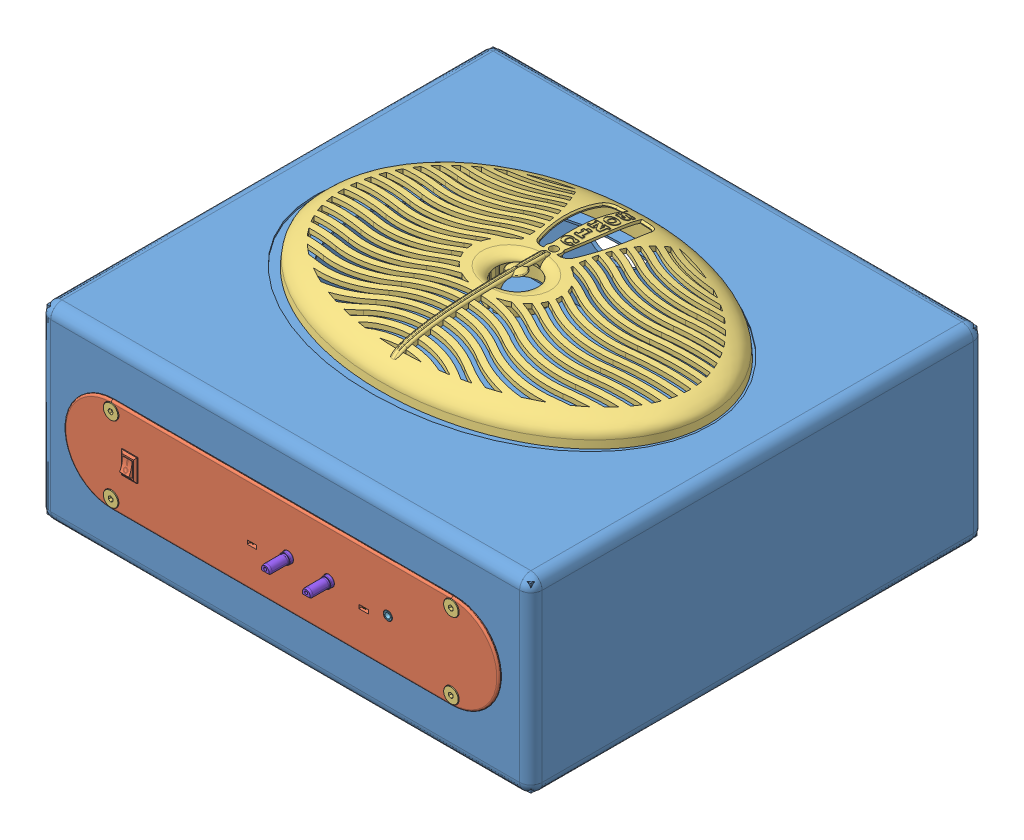
SolidWorks assembly HappyTunesAssembly, configuration Default. Lengths in mm.
Overall size (330.2 155.84 325.49).
147 component instances, 21 part files, 13 mates.
Components (placement in the parent):
- SpeakerBox-1: SpeakerBox [Default] at (77.636 124.7936 266.6745) size (330.2 127 304.8)
- FacePlate-1: FacePlate [Default] at (77.636 188.2936 419.0745) size (292.1 63.5 2.54)
- User Library-6x9 marine speaker-grille-1: User Library-6x9 marine speaker-grille [Default] at (78.9977 250.5236 265.0729) size (279.28 30.11 201.86)
- GateDriver-1: GateDriver [Default] at (239.7422 178.354 452.5745) x (-0.999998 0.002225 0) z (0.002225 0.999998 0) size (183.5 153.69 35.98)
  - GateDriver.step-1: GateDriver.step [Default] at origin size (183.5 153.69 35.98)
    - C_Rect_L7.0mm_W2.5mm_P5.00mm.step-1: C_Rect_L7.0mm_W2.5mm_P5.00mm.step [Default] at (155 -55 1.65) size (7 2.5 11.9)
      - SOLID.step-1: SOLID.step [Default] at origin size (7 2.5 11.9)
    - C_Rect_L7.0mm_W2.5mm_P5.00mm.step-2: C_Rect_L7.0mm_W2.5mm_P5.00mm.step [Default] at (151 -150.5 1.65) size (7 2.5 11.9)
      - SOLID.step-1: SOLID.step [Default] at origin size (7 2.5 11.9)
    - C_Rect_L7.0mm_W2.5mm_P5.00mm.step-3: C_Rect_L7.0mm_W2.5mm_P5.00mm.step [Default] at (164 -55 1.65) size (7 2.5 11.9)
      - SOLID.step-1: SOLID.step [Default] at origin size (7 2.5 11.9)
    - C_Rect_L7.0mm_W2.5mm_P5.00mm.step-4: C_Rect_L7.0mm_W2.5mm_P5.00mm.step [Default] at (139 -150.5 1.65) size (7 2.5 11.9)
      - SOLID.step-1: SOLID.step [Default] at origin size (7 2.5 11.9)
    - C_Rect_L7.0mm_W2.5mm_P5.00mm.step-5: C_Rect_L7.0mm_W2.5mm_P5.00mm.step [Default] at (112 -104.5 1.65) size (7 2.5 11.9)
      - SOLID.step-1: SOLID.step [Default] at origin size (7 2.5 11.9)
    - C_Rect_L7.0mm_W2.5mm_P5.00mm.step-6: C_Rect_L7.0mm_W2.5mm_P5.00mm.step [Default] at (112 -96.5 1.65) size (7 2.5 11.9)
      - SOLID.step-1: SOLID.step [Default] at origin size (7 2.5 11.9)
    - CUI_DEVICES_SJ1-3533NG.step-1: CUI_DEVICES_SJ1-3533NG.step [Default] at (90.5 -30.8 9.15) x (0 1 0) z (0 0 -1) size (18.05 8.2 15.6)
      - SOLID-0.step-1: SOLID-0.step [Default] at origin size (18.05 8.2 15.6)
    - PinHeader_1x06_P2.54mm_Vertical.step-1: PinHeader_1x06_P2.54mm_Vertical.step [Default] at (58.5 -55 1.65) x (-1 0 0) z (0 0 1) size (2.54 15.24 11.54)
      - SOLID-1.step-1: SOLID-1.step [Default] at origin size (2.54 15.24 11.54)
    - R_Axial_DIN0204_L3.6mm_D1.6mm_P7.62mm_Horizontal.step-1: R_Axial_DIN0204_L3.6mm_D1.6mm_P7.62mm_Horizontal.step [Default] at (71 -41.5 1.65) x (-1 0 0) z (0 0 1) size (8.12 1.6 4.72)
      - SOLID-2.step-1: SOLID-2.step [Default] at origin size (8.12 1.6 4.72)
    - R_Axial_DIN0204_L3.6mm_D1.6mm_P7.62mm_Horizontal.step-2: R_Axial_DIN0204_L3.6mm_D1.6mm_P7.62mm_Horizontal.step [Default] at (71 -47 1.65) x (-1 0 0) z (0 0 1) size (8.12 1.6 4.72)
      - SOLID-2.step-1: SOLID-2.step [Default] at origin size (8.12 1.6 4.72)
    - R_Axial_DIN0204_L3.6mm_D1.6mm_P7.62mm_Horizontal.step-3: R_Axial_DIN0204_L3.6mm_D1.6mm_P7.62mm_Horizontal.step [Default] at (82 -47 1.65) x (0 1 0) z (0 0 1) size (8.12 1.6 4.72)
      - SOLID-2.step-1: SOLID-2.step [Default] at origin size (8.12 1.6 4.72)
    - R_Axial_DIN0204_L3.6mm_D1.6mm_P7.62mm_Horizontal.step-4: R_Axial_DIN0204_L3.6mm_D1.6mm_P7.62mm_Horizontal.step [Default] at (97.5 -51 1.65) x (0 1 0) z (0 0 1) size (8.12 1.6 4.72)
      - SOLID-2.step-1: SOLID-2.step [Default] at origin size (8.12 1.6 4.72)
    - R_Axial_DIN0204_L3.6mm_D1.6mm_P7.62mm_Horizontal.step-5: R_Axial_DIN0204_L3.6mm_D1.6mm_P7.62mm_Horizontal.step [Default] at (153.5 -49.5 1.65) size (8.12 1.6 4.72)
      - SOLID-2.step-1: SOLID-2.step [Default] at origin size (8.12 1.6 4.72)
    - R_Axial_DIN0204_L3.6mm_D1.6mm_P7.62mm_Horizontal.step-6: R_Axial_DIN0204_L3.6mm_D1.6mm_P7.62mm_Horizontal.step [Default] at (164 -49.5 1.65) size (8.12 1.6 4.72)
      - SOLID-2.step-1: SOLID-2.step [Default] at origin size (8.12 1.6 4.72)
    - User Library-K091B0Z94 v1.step-1: User Library-K091B0Z94 v1.step [Default] at (157.5 -34 9.65) x (1 0 0) z (0 -1 0) size (9.8 16.06 30.49)
      - COMPOUND.step-1: COMPOUND.step [Default] at origin size (9.8 16.06 30.49)
    - User Library-K091B0Z94 v1.step-2: User Library-K091B0Z94 v1.step [Default] at (130 -34 9.65) x (1 0 0) z (0 -1 0) size (9.8 16.06 30.49)
      - COMPOUND.step-1: COMPOUND.step [Default] at origin size (9.8 16.06 30.49)
    - 3Pins SPDT switch SK-12D07 1P2T.step-1: 3Pins SPDT switch SK-12D07 1P2T.step [Default] at (111.35 -34.7 6.65) x (-1 0 0) z (0 0 1) size (8.6 6.94 7.5)
      - COMPOUND-3.step-1: COMPOUND-3.step [Default] at origin size (8.6 6.94 7.5)
    - SW_CuK_JS202011AQN_DPDT_Angled.step-1: SW_CuK_JS202011AQN_DPDT_Angled.step [Default] at (130.5 -59.5 1.65) x (-1 0 0) z (0 0 1) size (9 5.6 6.5)
      - SOLID-4.step-1: SOLID-4.step [Default] at origin size (9 5.6 6.5)
    - 3Pins SPDT switch SK-12D07 1P2T.step-2: 3Pins SPDT switch SK-12D07 1P2T.step [Default] at (186.85 -34.65 6.65) x (-1 0 0) z (0 0 1) size (8.6 6.94 7.5)
      - COMPOUND-3.step-1: COMPOUND-3.step [Default] at origin size (8.6 6.94 7.5)
    - TO-220-3_Vertical.step-1: TO-220-3_Vertical.step [Default] at (177.5 -151 1.65) size (10.25 4.46 28.53)
      - SOLID-5.step-1: SOLID-5.step [Default] at origin size (10.25 4.46 28.53)
    - TO-220-3_Vertical.step-2: TO-220-3_Vertical.step [Default] at (161.5 -151 1.65) size (10.25 4.46 28.53)
      - SOLID-5.step-1: SOLID-5.step [Default] at origin size (10.25 4.46 28.53)
    - DIP-8_W7.62mm_Socket.step-1: DIP-8_W7.62mm_Socket.step [Default] at (141 -51 1.65) size (10.16 10.16 7.79)
      - SOLID-6.step-1: SOLID-6.step [Default] at origin size (10.16 10.16 7.79)
    - D_DO-35_SOD27_P7.62mm_Horizontal.step-1: D_DO-35_SOD27_P7.62mm_Horizontal.step [Default] at (131 -93 1.65) x (0 1 0) z (0 0 1) size (8.12 2.33 5.01)
      - COMPOUND-7.step-1: COMPOUND-7.step [Default] at origin size (8.12 2.33 5.01)
    - C_Radial_D8.0mm_H7.0mm_P3.50mm.step-1: C_Radial_D8.0mm_H7.0mm_P3.50mm.step [Default] at (142 -87.5 1.65) x (-1 0 0) z (0 0 1) size (12.01 13.86 9)
      - SOLID-8.step-1: SOLID-8.step [Default] at origin size (12.01 13.86 9)
    - C_Rect_L7.0mm_W2.5mm_P5.00mm.step-7: C_Rect_L7.0mm_W2.5mm_P5.00mm.step [Default] at (143 -97 1.65) x (-1 0 0) z (0 0 1) size (7 2.5 11.9)
      - SOLID.step-1: SOLID.step [Default] at origin size (7 2.5 11.9)
    - C_Rect_L7.0mm_W2.5mm_P5.00mm.step-8: C_Rect_L7.0mm_W2.5mm_P5.00mm.step [Default] at (140.5 -134.5 1.65) x (-1 0 0) z (0 0 1) size (7 2.5 11.9)
      - SOLID.step-1: SOLID.step [Default] at origin size (7 2.5 11.9)
    - C_Rect_L7.0mm_W2.5mm_P5.00mm.step-9: C_Rect_L7.0mm_W2.5mm_P5.00mm.step [Default] at (201.5 -130 1.65) x (0 -1 0) z (0 0 1) size (7 2.5 11.9)
      - SOLID.step-1: SOLID.step [Default] at origin size (7 2.5 11.9)
    - D_DO-35_SOD27_P7.62mm_Horizontal.step-2: D_DO-35_SOD27_P7.62mm_Horizontal.step [Default] at (130 -129 1.65) x (0 1 0) z (0 0 1) size (8.12 2.33 5.01)
      - COMPOUND-7.step-1: COMPOUND-7.step [Default] at origin size (8.12 2.33 5.01)
    - C_Rect_L7.0mm_W2.5mm_P5.00mm.step-10: C_Rect_L7.0mm_W2.5mm_P5.00mm.step [Default] at (201.5 -89.5 1.65) x (0 -1 0) z (0 0 1) size (7 2.5 11.9)
      - SOLID.step-1: SOLID.step [Default] at origin size (7 2.5 11.9)
    - C_Radial_D8.0mm_H7.0mm_P3.50mm.step-2: C_Radial_D8.0mm_H7.0mm_P3.50mm.step [Default] at (139.5 -124 1.65) x (-1 0 0) z (0 0 1) size (12.01 13.86 9)
      - SOLID-8.step-1: SOLID-8.step [Default] at origin size (12.01 13.86 9)
    - C_Rect_L7.0mm_W2.5mm_P5.00mm.step-11: C_Rect_L7.0mm_W2.5mm_P5.00mm.step [Default] at (211 -93 1.65) x (0 -1 0) z (0 0 1) size (7 2.5 11.9)
      - SOLID.step-1: SOLID.step [Default] at origin size (7 2.5 11.9)
    - D_DO-41_SOD81_P10.16mm_Horizontal.step-1: D_DO-41_SOD81_P10.16mm_Horizontal.step [Default] at (152.5 -107.5 1.65) size (10.96 3.14 5.71)
      - SOLID-9.step-1: SOLID-9.step [Default] at origin size (10.96 3.14 5.71)
    - D_DO-41_SOD81_P10.16mm_Horizontal.step-2: D_DO-41_SOD81_P10.16mm_Horizontal.step [Default] at (153 -91.5 1.65) size (10.96 3.14 5.71)
      - SOLID-9.step-1: SOLID-9.step [Default] at origin size (10.96 3.14 5.71)
    - R_Axial_DIN0204_L3.6mm_D1.6mm_P7.62mm_Horizontal.step-7: R_Axial_DIN0204_L3.6mm_D1.6mm_P7.62mm_Horizontal.step [Default] at (161.5 -101.5 1.65) x (-1 0 0) z (0 0 1) size (8.12 1.6 4.72)
      - SOLID-2.step-1: SOLID-2.step [Default] at origin size (8.12 1.6 4.72)
    - L_CommonMode_Toroid_Vertical_L24.0mm_W16.3mm_Px10.16mm_Py20.32mm_muRATA_5200.step-1: L_CommonMode_Toroid_Vertical_L24.0mm_W16.3mm_Px10.16mm_Py20.32mm_muRATA_5200.step [Default] at (191.5 -83.5 1.65) x (0 1 0) z (0 0 1) size (24 16.3 30.48)
      - COMPOUND-10.step-1: COMPOUND-10.step [Default] at origin size (24 16.3 30.48)
    - L_CommonMode_Toroid_Vertical_L24.0mm_W16.3mm_Px10.16mm_Py20.32mm_muRATA_5200.step-2: L_CommonMode_Toroid_Vertical_L24.0mm_W16.3mm_Px10.16mm_Py20.32mm_muRATA_5200.step [Default] at (191.5 -123 1.65) x (0 1 0) z (0 0 1) size (24 16.3 30.48)
      - COMPOUND-10.step-1: COMPOUND-10.step [Default] at origin size (24 16.3 30.48)
    - TO-220-3_Vertical.step-3: TO-220-3_Vertical.step [Default] at (177 -87.5 1.65) x (0 -1 0) z (0 0 1) size (10.25 4.46 28.53)
      - SOLID-5.step-1: SOLID-5.step [Default] at origin size (10.25 4.46 28.53)
    - R_Axial_DIN0204_L3.6mm_D1.6mm_P7.62mm_Horizontal.step-8: R_Axial_DIN0204_L3.6mm_D1.6mm_P7.62mm_Horizontal.step [Default] at (161.5 -66.5 1.65) x (-1 0 0) z (0 0 1) size (8.12 1.6 4.72)
      - SOLID-2.step-1: SOLID-2.step [Default] at origin size (8.12 1.6 4.72)
    - TO-220-3_Vertical.step-4: TO-220-3_Vertical.step [Default] at (176.5 -105.5 1.65) x (0 -1 0) z (0 0 1) size (10.25 4.46 28.53)
      - SOLID-5.step-1: SOLID-5.step [Default] at origin size (10.25 4.46 28.53)
    - TO-220-3_Vertical.step-5: TO-220-3_Vertical.step [Default] at (176.5 -124.5 1.65) x (0 -1 0) z (0 0 1) size (10.25 4.46 28.53)
      - SOLID-5.step-1: SOLID-5.step [Default] at origin size (10.25 4.46 28.53)
    - TO-220-3_Vertical.step-6: TO-220-3_Vertical.step [Default] at (177 -72.5 1.65) x (0 -1 0) z (0 0 1) size (10.25 4.46 28.53)
      - SOLID-5.step-1: SOLID-5.step [Default] at origin size (10.25 4.46 28.53)
    - D_DO-41_SOD81_P10.16mm_Horizontal.step-3: D_DO-41_SOD81_P10.16mm_Horizontal.step [Default] at (152.5 -72.5 1.65) size (10.96 3.14 5.71)
      - SOLID-9.step-1: SOLID-9.step [Default] at origin size (10.96 3.14 5.71)
    - D_DO-41_SOD81_P10.16mm_Horizontal.step-4: D_DO-41_SOD81_P10.16mm_Horizontal.step [Default] at (150 -128.5 1.65) size (10.96 3.14 5.71)
      - SOLID-9.step-1: SOLID-9.step [Default] at origin size (10.96 3.14 5.71)
    - R_Axial_DIN0204_L3.6mm_D1.6mm_P7.62mm_Horizontal.step-9: R_Axial_DIN0204_L3.6mm_D1.6mm_P7.62mm_Horizontal.step [Default] at (162 -85.5 1.65) x (-1 0 0) z (0 0 1) size (8.12 1.6 4.72)
      - SOLID-2.step-1: SOLID-2.step [Default] at origin size (8.12 1.6 4.72)
    - R_Axial_DIN0204_L3.6mm_D1.6mm_P7.62mm_Horizontal.step-10: R_Axial_DIN0204_L3.6mm_D1.6mm_P7.62mm_Horizontal.step [Default] at (159 -122 1.65) x (-1 0 0) z (0 0 1) size (8.12 1.6 4.72)
      - SOLID-2.step-1: SOLID-2.step [Default] at origin size (8.12 1.6 4.72)
    - R_Axial_DIN0204_L3.6mm_D1.6mm_P7.62mm_Horizontal.step-11: R_Axial_DIN0204_L3.6mm_D1.6mm_P7.62mm_Horizontal.step [Default] at (166.5 -72.5 1.65) x (0 -1 0) z (0 0 1) size (8.12 1.6 4.72)
      - SOLID-2.step-1: SOLID-2.step [Default] at origin size (8.12 1.6 4.72)
    - R_Axial_DIN0204_L3.6mm_D1.6mm_P7.62mm_Horizontal.step-12: R_Axial_DIN0204_L3.6mm_D1.6mm_P7.62mm_Horizontal.step [Default] at (166.5 -107.5 1.65) x (0 -1 0) z (0 0 1) size (8.12 1.6 4.72)
      - SOLID-2.step-1: SOLID-2.step [Default] at origin size (8.12 1.6 4.72)
    - R_Axial_DIN0204_L3.6mm_D1.6mm_P7.62mm_Horizontal.step-13: R_Axial_DIN0204_L3.6mm_D1.6mm_P7.62mm_Horizontal.step [Default] at (167.5 -91.5 1.65) x (0 -1 0) z (0 0 1) size (8.12 1.6 4.72)
      - SOLID-2.step-1: SOLID-2.step [Default] at origin size (8.12 1.6 4.72)
    - R_Axial_DIN0204_L3.6mm_D1.6mm_P7.62mm_Horizontal.step-14: R_Axial_DIN0204_L3.6mm_D1.6mm_P7.62mm_Horizontal.step [Default] at (165 -128.5 1.65) x (0 -1 0) z (0 0 1) size (8.12 1.6 4.72)
      - SOLID-2.step-1: SOLID-2.step [Default] at origin size (8.12 1.6 4.72)
    - DIP-14_W7.62mm_Socket.step-1: DIP-14_W7.62mm_Socket.step [Default] at (128 -113.5 1.65) x (0 1 0) z (0 0 1) size (10.16 17.78 7.79)
      - SOLID-11.step-1: SOLID-11.step [Default] at origin size (10.16 17.78 7.79)
    - DIP-14_W7.62mm_Socket.step-2: DIP-14_W7.62mm_Socket.step [Default] at (128 -79.5 1.65) x (0 1 0) z (0 0 1) size (10.16 17.78 7.79)
      - SOLID-11.step-1: SOLID-11.step [Default] at origin size (10.16 17.78 7.79)
    - TO-220-3_Vertical.step-7: TO-220-3_Vertical.step [Default] at (114 -68 1.65) x (0 -1 0) z (0 0 1) size (10.25 4.46 28.53)
      - SOLID-5.step-1: SOLID-5.step [Default] at origin size (10.25 4.46 28.53)
    - TO-220-3_Vertical.step-8: TO-220-3_Vertical.step [Default] at (114 -82 1.65) x (0 -1 0) z (0 0 1) size (10.25 4.46 28.53)
      - SOLID-5.step-1: SOLID-5.step [Default] at origin size (10.25 4.46 28.53)
    - R_Axial_DIN0204_L3.6mm_D1.6mm_P7.62mm_Horizontal.step-15: R_Axial_DIN0204_L3.6mm_D1.6mm_P7.62mm_Horizontal.step [Default] at (120.5 -63 1.65) x (0 -1 0) z (0 0 1) size (8.12 1.6 4.72)
      - SOLID-2.step-1: SOLID-2.step [Default] at origin size (8.12 1.6 4.72)
    - R_Axial_DIN0204_L3.6mm_D1.6mm_P7.62mm_Horizontal.step-16: R_Axial_DIN0204_L3.6mm_D1.6mm_P7.62mm_Horizontal.step [Default] at (108.5 -82 1.65) x (0 -1 0) z (0 0 1) size (8.12 1.6 4.72)
      - SOLID-2.step-1: SOLID-2.step [Default] at origin size (8.12 1.6 4.72)
    - R_Axial_DIN0204_L3.6mm_D1.6mm_P7.62mm_Horizontal.step-17: R_Axial_DIN0204_L3.6mm_D1.6mm_P7.62mm_Horizontal.step [Default] at (120.5 -77 1.65) x (0 -1 0) z (0 0 1) size (8.12 1.6 4.72)
      - SOLID-2.step-1: SOLID-2.step [Default] at origin size (8.12 1.6 4.72)
    - R_Axial_DIN0204_L3.6mm_D1.6mm_P7.62mm_Horizontal.step-18: R_Axial_DIN0204_L3.6mm_D1.6mm_P7.62mm_Horizontal.step [Default] at (109 -68 1.65) x (0 -1 0) z (0 0 1) size (8.12 1.6 4.72)
      - SOLID-2.step-1: SOLID-2.step [Default] at origin size (8.12 1.6 4.72)
    - Pin_D1.3mm_L11.0mm.step-1: Pin_D1.3mm_L11.0mm.step [Default] at (200 -44 1.65) size (2.5 2.89 11)
      - SOLID-12.step-1: SOLID-12.step [Default] at origin size (2.5 2.89 11)
    - Pin_D1.3mm_L11.0mm.step-2: Pin_D1.3mm_L11.0mm.step [Default] at (107.5 -56.5 1.65) size (2.5 2.89 11)
      - SOLID-12.step-1: SOLID-12.step [Default] at origin size (2.5 2.89 11)
    - Pin_D1.3mm_L11.0mm.step-3: Pin_D1.3mm_L11.0mm.step [Default] at (107.5 -50 1.65) size (2.5 2.89 11)
      - SOLID-12.step-1: SOLID-12.step [Default] at origin size (2.5 2.89 11)
    - Pin_D1.3mm_L11.0mm.step-4: Pin_D1.3mm_L11.0mm.step [Default] at (149 -70 1.65) size (2.5 2.89 11)
      - SOLID-12.step-1: SOLID-12.step [Default] at origin size (2.5 2.89 11)
    - Pin_D1.3mm_L11.0mm.step-5: Pin_D1.3mm_L11.0mm.step [Default] at (148.5 -89 1.65) size (2.5 2.89 11)
      - SOLID-12.step-1: SOLID-12.step [Default] at origin size (2.5 2.89 11)
    - Pin_D1.3mm_L11.0mm.step-6: Pin_D1.3mm_L11.0mm.step [Default] at (148.5 -103 1.65) size (2.5 2.89 11)
      - SOLID-12.step-1: SOLID-12.step [Default] at origin size (2.5 2.89 11)
    - Pin_D1.3mm_L11.0mm.step-7: Pin_D1.3mm_L11.0mm.step [Default] at (147.5 -119 1.65) size (2.5 2.89 11)
      - SOLID-12.step-1: SOLID-12.step [Default] at origin size (2.5 2.89 11)
    - Pin_D1.3mm_L11.0mm.step-8: Pin_D1.3mm_L11.0mm.step [Default] at (186 -91.5 1.65) size (2.5 2.89 11)
      - SOLID-12.step-1: SOLID-12.step [Default] at origin size (2.5 2.89 11)
    - Pin_D1.3mm_L11.0mm.step-9: Pin_D1.3mm_L11.0mm.step [Default] at (183.5 -123 1.65) size (2.5 2.89 11)
      - SOLID-12.step-1: SOLID-12.step [Default] at origin size (2.5 2.89 11)
    - Pin_D1.3mm_L11.0mm.step-10: Pin_D1.3mm_L11.0mm.step [Default] at (215 -88 1.65) size (2.5 2.89 11)
      - SOLID-12.step-1: SOLID-12.step [Default] at origin size (2.5 2.89 11)
    - Pin_D1.3mm_L11.0mm.step-11: Pin_D1.3mm_L11.0mm.step [Default] at (215 -105 1.65) size (2.5 2.89 11)
      - SOLID-12.step-1: SOLID-12.step [Default] at origin size (2.5 2.89 11)
    - _autosave-GateDriver PCB.step-1: _autosave-GateDriver PCB.step [Default] at origin size (183.5 133 1.6)
- User Library-KCD11-A-101O11RB-1: User Library-KCD11-A-101O11RB [По умолчанию] at (-24.019 188.2588 406.4145) size (10.5 15 19.1)
- M5 x 20 csk machine screw-1: M5 x 20 csk machine screw [B18.3.5M - 5 x 0.8 x 20 Socket FCHS  -- 20S] at (-36.664 213.6936 422.0145) x (0 0 -1) z (-0.03822 0.999269 0) size (20 9.75 9.75)
- M5 x 20 csk machine screw-2: M5 x 20 csk machine screw [B18.3.5M - 5 x 0.8 x 20 Socket FCHS  -- 20S] at (191.936 213.6936 422.0145) x (0 0 -1) z (1 0 0) size (20 9.75 9.75)
- M5 x 20 csk machine screw-3: M5 x 20 csk machine screw [B18.3.5M - 5 x 0.8 x 20 Socket FCHS  -- 20S] at (191.936 162.8936 422.0145) x (0 0 -1) z (1 0 0) size (20 9.75 9.75)
- M5 x 20 csk machine screw-4: M5 x 20 csk machine screw [B18.3.5M - 5 x 0.8 x 20 Socket FCHS  -- 20S] at (-36.664 162.8936 422.0145) x (0 0 -1) z (1 0 0) size (20 9.75 9.75)
Mates (geometry in assembly coordinates):
- Coincident1: coincident anti-aligned: plane of SpeakerBox-1 through (-87.464 251.7936 419.0745) normal (0 0 1); plane of FacePlate-1 through (192.112 188.2942 419.0745) normal (0 0 -1)
- Coincident2: coincident anti-aligned: plane of FacePlate-1 through (192.112 188.2942 419.0745) normal (0 0 -1); plane of GateDriver-1/GateDriver.step-1/_autosave-GateDriver PCB.step-1 through (198.9862 178.4927 419.0745) normal (0 0 1)
- Tangent5: tangent aligned: cylinder of ? through (109.7589 187.7236 413.9945) axis (0 0 1) radius 3.683; face of GateDriver-1/GateDriver.step-1/User Library-K091B0Z94 v1.step-2/COMPOUND.step-1
- Tangent10: tangent: cylinder of FacePlate-1 through (149.3624 187.363 413.9945) axis (0 0 1) radius 3.048; curve of GateDriver-1/GateDriver.step-1/CUI_DEVICES_SJ1-3533NG.step-1/SOLID-0.step-1
- Coincident4: coincident anti-aligned: plane of FacePlate-1 through (192.112 188.2942 421.6145) normal (0 0 1); plane of User Library-KCD11-A-101O11RB-1 through (-23.8376 186.7633 421.6145) normal (0 0 -1)
- Coincident5: coincident: plane of FacePlate-1 through (-28.2761 193.7525 413.9945) normal (0.006928 -0.999976 0); line of User Library-KCD11-A-101O11RB-1 through (-21.8863 193.7968 420.4643) axis (-0.999976 -0.006928 0)
- Coincident6: coincident anti-aligned: plane of FacePlate-1 through (-19.2896 179.8444 413.9945) normal (-0.999976 -0.006928 0); plane of User Library-KCD11-A-101O11RB-1 through (-19.3377 186.7945 406.4145) normal (0.999976 0.006928 0)
- Coincident7: coincident aligned: cone of FacePlate-1 through (-36.6585 212.1099 421.6145) axis (0 0 -1); cone of M5 x 20 csk machine screw-1 through (-36.6585 212.1099 421.2895) axis (0 0 -1)
- Coincident8: coincident aligned: cone of FacePlate-1 through (191.936 213.6936 421.6145) axis (0 0 -1); cone of M5 x 20 csk machine screw-2 through (191.936 213.6936 421.2895) axis (0 0 -1)
- Coincident9: coincident aligned: cone of FacePlate-1 through (192.2879 162.8948 421.6145) axis (0 0 -1); cone of M5 x 20 csk machine screw-3 through (192.2879 162.8948 421.2895) axis (0 0 -1)
- Coincident10: coincident aligned: cone of FacePlate-1 through (-36.3066 161.3111 421.6145) axis (0 0 -1); cone of M5 x 20 csk machine screw-4 through (-36.3066 161.3111 421.2895) axis (0 0 -1)
- Concentric4: concentric aligned: cylinder of SpeakerBox-1 through (191.936 213.6936 416.5345) axis (0 0 1) radius 2.5; cylinder of FacePlate-1 through (191.936 213.6936 421.6145) axis (0 0 1) radius 2.75
- Concentric5: concentric aligned: cylinder of SpeakerBox-1 through (-36.664 162.8936 416.5345) axis (0 0 1) radius 2.5; cylinder of FacePlate-1 through (-36.664 162.8936 421.6145) axis (0 0 1) radius 2.75
